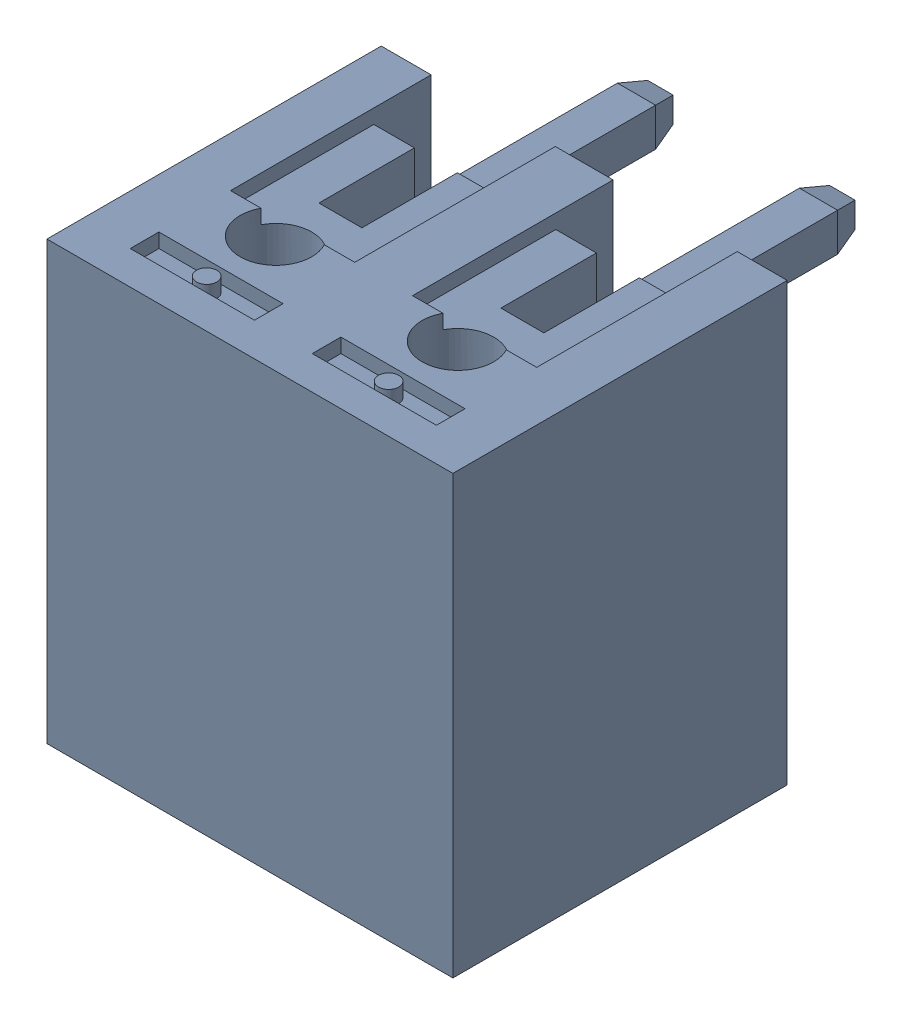
SolidWorks assembly CN1, configuration Default. Lengths in mm.
Overall size (8.5 9.15 10.5).
2 component instances, 1 part files, 0 mates.
Components (placement in the parent):
- CONN-TH_2P-P3.81_KF2EDGR-3.81-2P-1: CONN-TH_2P-P3.81_KF2EDGR-3.81-2P [Default] at origin size (8.5 9.15 10.5)
  - =_[0_1_1_5]-1: =_[0_1_1_5] [Default] at (-1.905 -0.35 0) size (8.5 9.15 10.5)
